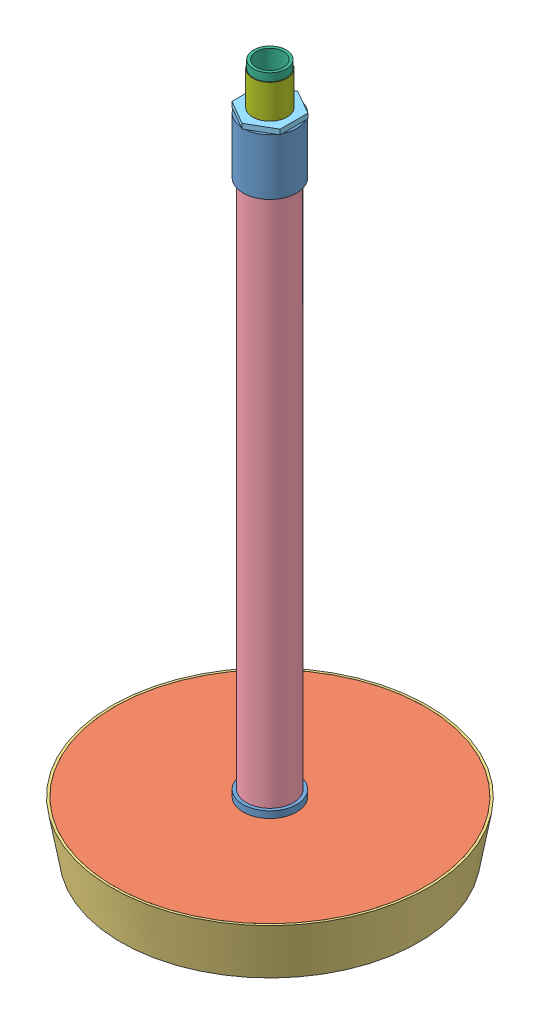
SolidWorks assembly WELLHEAD, configuration Default. Lengths in mm.
Overall size (406.66 886.97 406.66).
8 component instances, 7 part files, 18 mates.
Components (placement in the parent):
- 2 COUPLING-1: 2 COUPLING [4880K76] at (0 -27.5082 0) x (0 -1 0) z (0 0 1) size (71.98 68.71 68.71)
- CONCRETE-1: CONCRETE [Default] x (0.999859 0 0.016797) z (-0.016797 0 0.999859) size (400 63.5 400)
- PAN-1: PAN [Default] at origin size (406.09 66.5 406.09)
- 2 PVC PIPE 75CM-1: 2 PVC PIPE 75CM [48925K96] at (0 348.6856 0) x (1 0 0) z (0 1 0) size (60.32 60.32 750)
- 2 COUPLING-2: 2 COUPLING [4880K76] at (0 724.8794 0) x (0 -1 0) z (0 0 1) size (71.98 68.71 68.71)
- 2 X 1 1-4 BUSHING-1: 2 X 1 1-4 BUSHING [4880K339] at (0 726.74 0) x (0 -1 0) z (-0.5 0 0.866025) size (40.48 71.49 61.91)
- 1 1-4 PVC PIPE 8 1-2CM-1: 1 1-4 PVC PIPE 8 1-2CM [48925K94] at (0 777.9712 0) x (1 0 0) z (0 1 0) size (42.16 42.16 85)
- VELCRO C-1: VELCRO C [Default] at (0 767.2212 0) x (0.995049 0 0.099389) z (-0.099389 0 0.995049) size (44 43.25 44)
Mates (geometry in assembly coordinates):
- Coincident1: coincident: plane of PAN-1 through (0 0 0) normal (0 0 1); plane of assembly through (0 0 0) normal (0 0 1)
- Coincident2: coincident: plane of PAN-1 through (0 0 0) normal (0 1 0); plane of assembly through (0 0 0) normal (0 1 0)
- Coincident3: coincident aligned: plane of PAN-1 through (0 0 0) normal (1 0 0); plane of assembly through (0 0 0) normal (1 0 0)
- Coincident6: coincident anti-aligned: plane of 2 COUPLING-1 through (-34.3535 -63.5 0) normal (0 -1 0); plane of PAN-1 through (0 -63.5 0) normal (0 1 0)
- Concentric2: concentric anti-aligned: cone of 2 COUPLING-1 through (0 -26.3144 0) axis (0 -1 0); circle of PAN-1
- Coincident9: coincident aligned: plane of CONCRETE-1 through (199.9718 0 3.3595) normal (0 1 0); plane of PAN-1 through (200 0 0) normal (0 1 0)
- Concentric3: concentric anti-aligned: cone of 2 COUPLING-1 through (0 -26.3144 0) axis (0 -1 0); cylinder of CONCRETE-1 through (0 -63.5 0) axis (0 1 0) radius 34.3535
- Coincident10: coincident anti-aligned: plane of 2 COUPLING-1 through (-30.0863 -26.3144 0) normal (0 1 0); plane of 2 PVC PIPE 75CM-1 through (0 -26.3144 0) normal (0 -1 0)
- Concentric4: concentric aligned: cone of 2 COUPLING-1 through (0 -26.3144 0) axis (0 -1 0); cylinder of 2 PVC PIPE 75CM-1 through (0 723.6856 0) axis (0 -1 0) radius 30.1625
- Coincident11: coincident anti-aligned: plane of 2 PVC PIPE 75CM-1 through (0 723.6856 0) normal (0 1 0); plane of 2 COUPLING-2 through (-30.0863 723.6856 0) normal (0 -1 0)
- Concentric5: concentric anti-aligned: cylinder of 2 PVC PIPE 75CM-1 through (0 723.6856 0) axis (0 -1 0) radius 30.1625; cylinder of 2 COUPLING-2 through (0 760.8712 0) axis (0 1 0) radius 34.3535
- Concentric6: concentric anti-aligned: cone of 2 COUPLING-2 through (0 726.0732 0) axis (0 -1 0); cylinder of 2 X 1 1-4 BUSHING-1 through (0 767.2212 0) axis (0 1 0) radius 30.1625
- Coincident12: coincident anti-aligned: plane of 2 COUPLING-2 through (-34.3535 760.8712 0) normal (0 1 0); plane of 2 X 1 1-4 BUSHING-1 through (30.9563 760.8712 17.8726) normal (0 -1 0)
- Parallel1: parallel aligned: plane of 2 X 1 1-4 BUSHING-1 through (30.9563 760.8712 17.8726) normal (1 0 0); plane of assembly
- Coincident14: coincident anti-aligned: plane of 2 X 1 1-4 BUSHING-1 through (-15.178 735.4712 -8.763) normal (0 1 0); plane of 1 1-4 PVC PIPE 8 1-2CM-1 through (0 735.4712 0) normal (0 -1 0)
- Concentric7: concentric aligned: cone of 2 X 1 1-4 BUSHING-1 through (0 735.4712 0) axis (0 -1 0); cylinder of 1 1-4 PVC PIPE 8 1-2CM-1 through (0 820.4712 0) axis (0 -1 0) radius 21.082
- Concentric8: concentric aligned: cylinder of 1 1-4 PVC PIPE 8 1-2CM-1 through (0 820.4712 0) axis (0 -1 0) radius 21.082; cylinder of VELCRO C-1 through (0 810.4712 0) axis (0 -1 0) radius 21.08
- Coincident15: coincident anti-aligned: plane of 2 X 1 1-4 BUSHING-1 through (-26.1215 767.2212 -15.0812) normal (0 1 0); plane of VELCRO C-1 through (0 767.2212 0) normal (0 -1 0)
